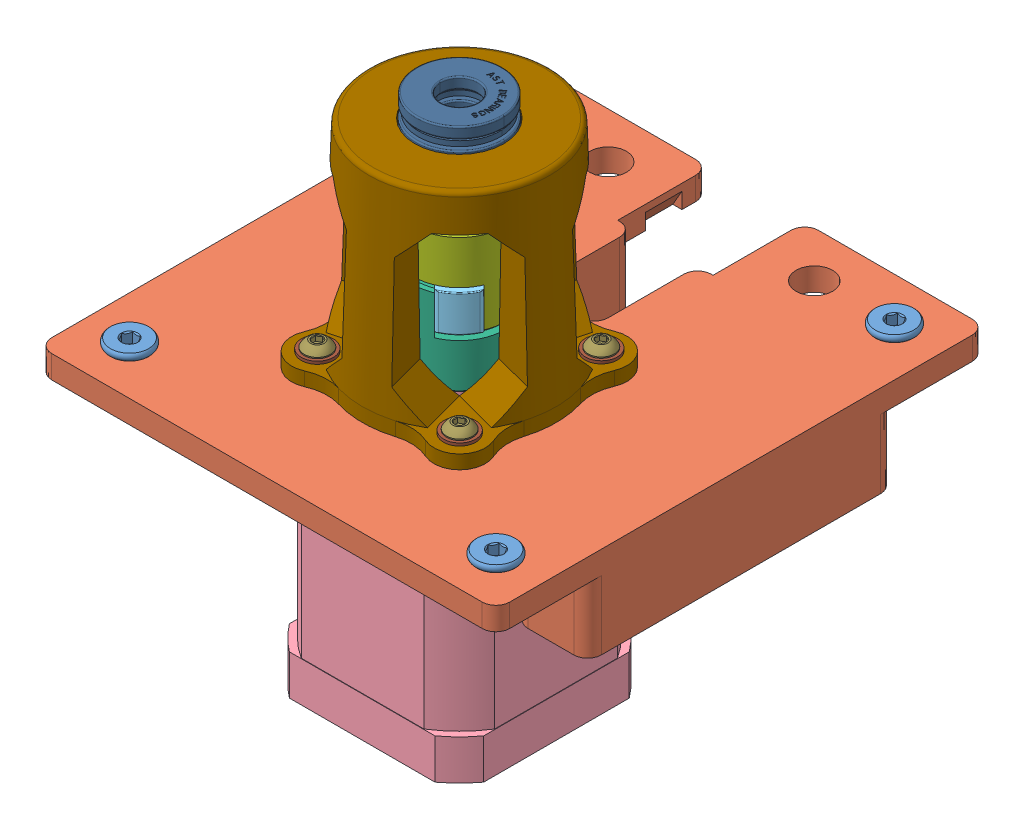
SolidWorks assembly back_z_plate_assembly, configuration Default. Lengths in mm.
Overall size (100 112 107).
27 component instances, 12 part files, 21 mates.
Components (placement in the parent):
- m5_low_profile_screw_template_M5 x 10-1: m5_low_profile_screw_template_M5 x 10 [Default] at (79.03 19.0109 49.0072) x (0 -1 0) z (0 0 1) size (11.62 9 9)
- back_z_motor_plate_Back Z Motor Plate-1: back_z_motor_plate_Back Z Motor Plate [Default] at (169.03 24.0109 -47.9928) x (-1 0 0) z (0 0 -1) size (100 20 107)
- m5_low_profile_screw_template_M5 x 10-2: m5_low_profile_screw_template_M5 x 10 [Default] at (159.03 19.0109 -37.9928) x (0 -1 0) z (0 0 1) size (11.62 9 9)
- m5_low_profile_screw_template_M5 x 10-3: m5_low_profile_screw_template_M5 x 10 [Default] at (79.03 19.0109 -37.9928) x (0 -1 0) z (0 0 1) size (11.62 9 9)
- m5_low_profile_screw_template_M5 x 10-4: m5_low_profile_screw_template_M5 x 10 [Default] at (159.03 19.0109 49.0072) x (0 -1 0) z (0 0 1) size (11.62 9 9)
- m5_locking_t_nut_20x20_generic-1: m5_locking_t_nut_20x20_generic [Default] at (159.03 19.5109 46.0072) size (10 4.5 6)
- m5_locking_t_nut_20x20_generic-2: m5_locking_t_nut_20x20_generic [Default] at (79.03 19.5109 46.0072) size (10 4.5 6)
- m5_locking_t_nut_20x20_generic-3: m5_locking_t_nut_20x20_generic [Default] at (159.03 19.5109 -40.9928) size (10 4.5 6)
- m5_locking_t_nut_20x20_generic-4: m5_locking_t_nut_20x20_generic [Default] at (79.3076 19.5109 -40.9799) x (0.99571 0 0.092531) z (-0.092531 0 0.99571) size (10 4.5 6)
- z_motor_thrust_assy_printed^back_z_plate_assembly-1: z_motor_thrust_assy_printed^back_z_plate_assembly [Default] at origin size (42.42 112 42.42) (virtual)
  - z_motor_thrust_coupling_assembly_3-1: z_motor_thrust_coupling_assembly_3 [Default] at (547.6945 -11.7621 -290.9574) x (0 0 1) z (-1 0 0) size (42.42 92 42.42)
    - 17HM19-2004S-1: 17HM19-2004S [Default] at (307.9646 28.773 428.6645) x (0 0 -1) z (0 1 0) size (42.42 42.42 72)
    - couplings_cajc20-rd-5-8-1: couplings_cajc20-rd-5-8 [Default] at (307.9646 57.773 428.6645) x (0 1 0) z (0 0 1) size (30 20 20)
      - couplings_cajc20-rd-5-8_01-1: couplings_cajc20-rd-5-8_01 [Default] at origin size (8 18.12 18.12)
      - couplings_cajc20-rd-5-8_02-1: couplings_cajc20-rd-5-8_02 [Default] at origin size (19 20 19.99)
      - couplings_cajc20-rd-5-8_03-1: couplings_cajc20-rd-5-8_03 [Default] at origin size (19 19.99 20)
  - NEMA17_spacer_plate_7mm-1: NEMA17_spacer_plate_7mm [Default] at (119.03 24.0109 17.0072) x (-1 0 0) z (0 -1 0) size (42.3 42.3 7)
  - thrust_cage-1: thrust_cage [Default] at (119.03 44.6637 17.0072) x (0.002418 0 0.999997) z (-0.999997 0 0.002418) size (42.3 47 42.3)
  - AST_Bearings_F8-19M-1: AST_Bearings_F8-19M [Default] at (119.03 77.5109 17.0072) x (0.99905 0 -0.043582) z (0.043582 0 0.99905) size (19 7 19)
  - m3_stainless_steel_washer_90965A130-1: m3_stainless_steel_washer_90965A130 [90965A130] at (134.5301 32.0109 1.5071) x (1 0 0) z (0 1 0) size (7 7 0.6)
  - m3_stainless_steel_washer_90965A130-2: m3_stainless_steel_washer_90965A130 [90965A130] at (134.605 32.0109 32.5071) x (1 0 -0.000026) z (0 1 0) size (7 7 0.6)
  - m3_stainless_steel_washer_90965A130-3: m3_stainless_steel_washer_90965A130 [90965A130] at (103.5301 32.0109 1.5821) x (1 0 0) z (0 1 0) size (7 7 0.6)
  - m3_stainless_steel_washer_90965A130-4: m3_stainless_steel_washer_90965A130 [90965A130] at (103.6051 32.0109 32.582) x (1 0 0) z (0 1 0) size (7 7 0.6)
  - m3_20mm_buttohead_screw_92095A185-1: m3_20mm_buttohead_screw_92095A185 [92095A185] at (103.5301 34.2609 1.5821) x (1 0 0) z (0 1 0) size (5.7 5.7 21.83)
  - m3_20mm_buttohead_screw_92095A185-2: m3_20mm_buttohead_screw_92095A185 [92095A185] at (103.6051 34.2609 32.582) x (1 0 0) z (0 1 0) size (5.7 5.7 21.83)
  - m3_20mm_buttohead_screw_92095A185-3: m3_20mm_buttohead_screw_92095A185 [92095A185] at (134.5301 34.2609 1.5071) x (1 0 0) z (0 1 0) size (5.7 5.7 21.83)
  - m3_20mm_buttohead_screw_92095A185-4: m3_20mm_buttohead_screw_92095A185 [92095A185] at (134.605 34.2609 32.5071) x (1 0 0) z (0 1 0) size (5.7 5.7 21.83)
Mates (geometry in assembly coordinates):
- Coincident4: coincident anti-aligned: plane of back_z_motor_plate_Back Z Motor Plate-1 through (169.03 29.0109 -47.9928) normal (0 1 0); plane of m5_low_profile_screw_template_M5 x 10-4 through (163.1914 29.0109 49.0072) normal (0 -1 0)
- Concentric5: concentric anti-aligned: cylinder of back_z_motor_plate_Back Z Motor Plate-1 through (159.03 29.0109 49.0072) axis (0 1 0) radius 2.65; cylinder of m5_low_profile_screw_template_M5 x 10-4 through (159.03 29.0109 49.0072) axis (0 -1 0) radius 2.5
- Coincident5: coincident anti-aligned: plane of m5_low_profile_screw_template_M5 x 10-1 through (83.1914 29.0109 49.0072) normal (0 -1 0); plane of back_z_motor_plate_Back Z Motor Plate-1 through (169.03 29.0109 -47.9928) normal (0 1 0)
- Concentric6: concentric anti-aligned: cylinder of m5_low_profile_screw_template_M5 x 10-1 through (79.03 29.0109 49.0072) axis (0 -1 0) radius 2.5; cylinder of back_z_motor_plate_Back Z Motor Plate-1 through (79.03 29.0109 49.0072) axis (0 1 0) radius 2.65
- Coincident6: coincident anti-aligned: plane of back_z_motor_plate_Back Z Motor Plate-1 through (169.03 29.0109 -47.9928) normal (0 1 0); plane of m5_low_profile_screw_template_M5 x 10-3 through (83.1914 29.0109 -37.9928) normal (0 -1 0)
- Concentric7: concentric anti-aligned: cylinder of back_z_motor_plate_Back Z Motor Plate-1 through (79.03 29.0109 -37.9928) axis (0 1 0) radius 2.65; cylinder of m5_low_profile_screw_template_M5 x 10-3 through (79.03 29.0109 -37.9928) axis (0 -1 0) radius 2.5
- Coincident7: coincident anti-aligned: plane of back_z_motor_plate_Back Z Motor Plate-1 through (169.03 29.0109 -47.9928) normal (0 1 0); plane of m5_low_profile_screw_template_M5 x 10-2 through (163.1914 29.0109 -37.9928) normal (0 -1 0)
- Concentric8: concentric anti-aligned: cylinder of back_z_motor_plate_Back Z Motor Plate-1 through (159.03 29.0109 -37.9928) axis (0 1 0) radius 2.65; cylinder of m5_low_profile_screw_template_M5 x 10-2 through (159.03 29.0109 -37.9928) axis (0 -1 0) radius 2.5
- Coincident9: coincident anti-aligned: plane of back_z_motor_plate_Back Z Motor Plate-1 through (169.03 24.0109 -47.9928) normal (0 -1 0); plane of m5_locking_t_nut_20x20_generic-2 through (76.03 24.0109 52.0072) normal (0 1 0)
- Concentric11: concentric anti-aligned: cylinder of m5_low_profile_screw_template_M5 x 10-1 through (79.03 29.0109 49.0072) axis (0 -1 0) radius 2.5; circle of m5_locking_t_nut_20x20_generic-2
- Concentric12: concentric anti-aligned: cylinder of m5_low_profile_screw_template_M5 x 10-4 through (159.03 29.0109 49.0072) axis (0 -1 0) radius 2.5; circle of m5_locking_t_nut_20x20_generic-1
- Coincident10: coincident anti-aligned: plane of back_z_motor_plate_Back Z Motor Plate-1 through (169.03 24.0109 -47.9928) normal (0 -1 0); plane of m5_locking_t_nut_20x20_generic-1 through (156.03 24.0109 52.0072) normal (0 1 0)
- Coincident11: coincident anti-aligned: plane of back_z_motor_plate_Back Z Motor Plate-1 through (129.43 24.0109 -47.9928) normal (0 -1 0); plane of m5_locking_t_nut_20x20_generic-3 through (156.03 24.0109 -34.9928) normal (0 1 0)
- Concentric13: concentric anti-aligned: cylinder of m5_low_profile_screw_template_M5 x 10-2 through (159.03 29.0109 -37.9928) axis (0 -1 0) radius 2.5; cylinder of m5_locking_t_nut_20x20_generic-3 through (159.03 24.0109 -37.9928) axis (0 1 0) radius 2.1
- Concentric14: concentric anti-aligned: cylinder of m5_low_profile_screw_template_M5 x 10-3 through (79.03 29.0109 -37.9928) axis (0 -1 0) radius 2.5; cylinder of m5_locking_t_nut_20x20_generic-4 through (79.03 24.0109 -37.9928) axis (0 1 0) radius 2.1
- Coincident12: coincident anti-aligned: plane of back_z_motor_plate_Back Z Motor Plate-1 through (69.03 24.0109 -47.9928) normal (0 -1 0); plane of m5_locking_t_nut_20x20_generic-4 through (75.7653 24.0109 -35.2833) normal (0 1 0)
- Concentric37: concentric aligned: circle of back_z_motor_plate_Back Z Motor Plate-1; circle of Assem1^back_z_plate_assembly-1/NEMA17_spacer_plate_7mm-1
- Coincident27: coincident anti-aligned: plane of back_z_motor_plate_Back Z Motor Plate-1 through (169.03 24.0109 -47.9928) normal (0 -1 0); plane of Assem1^back_z_plate_assembly-1/NEMA17_spacer_plate_7mm-1 through (119.03 24.0109 17.0072) normal (0 1 0)
- Concentric38: concentric aligned: cylinder of back_z_motor_plate_Back Z Motor Plate-1 through (134.53 24.0109 1.5072) axis (0 -1 0) radius 1.7; cylinder of Assem1^back_z_plate_assembly-1/NEMA17_spacer_plate_7mm-1 through (134.53 17.0109 1.5072) axis (0 -1 0) radius 1.7
- Concentric39: concentric anti-aligned: cylinder of back_z_motor_plate_Back Z Motor Plate-1 through (134.53 24.0109 1.5072) axis (0 -1 0) radius 1.7; cylinder of z_motor_thrust_assy_printed^back_z_plate_assembly-1/thrust_cage-1 through (134.5301 32.0109 1.5071) axis (0 1 0) radius 1.7
- Concentric40: concentric aligned: circle of back_z_motor_plate_Back Z Motor Plate-1; circle of Assem1^back_z_plate_assembly-1/z_motor_thrust_coupling_assembly_3-1/17HM19-2004S-1
